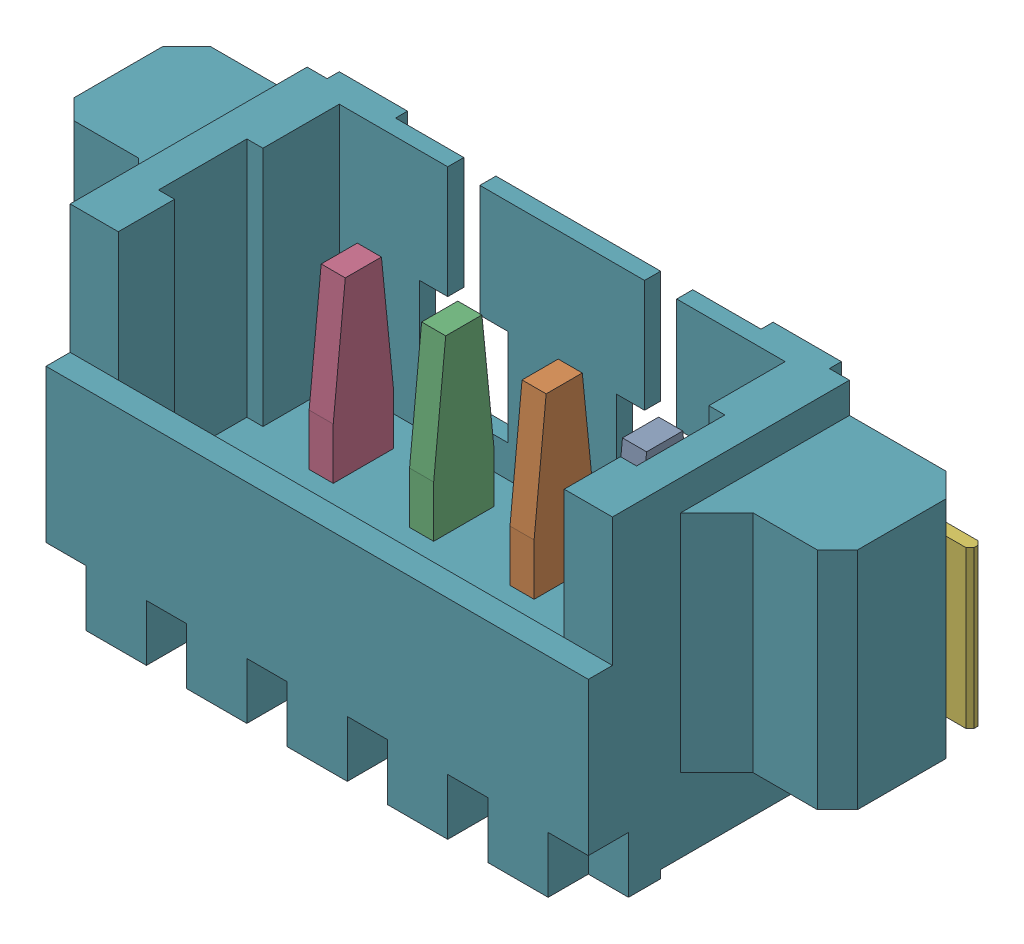
SolidWorks assembly J13, configuration Default. Lengths in mm.
Overall size (9.75 5.4 3.41).
8 component instances, 3 part files, 0 mates.
Components (placement in the parent):
- 653104131822-1: 653104131822 [Default] at (105.1001 84.1 1.69) x (-1 0 0) z (0 0 1) size (9.75 5.4 3.41)
  - 6531xx131822_PIN_2-1: 6531xx131822_PIN_2 [Default] at (-1.875 2.7 -0.425) x (1 0 0) z (0 -1 0) size (0.3 1.48 4.54)
  - 6531xx131822_PIN_2-2: 6531xx131822_PIN_2 [Default] at (-0.625 2.7 -0.425) x (1 0 0) z (0 -1 0) size (0.3 1.48 4.54)
  - 6531xx131822_PIN_2-3: 6531xx131822_PIN_2 [Default] at (0.625 2.7 -0.425) x (1 0 0) z (0 -1 0) size (0.3 1.48 4.54)
  - 6531xx131822_PIN_2-4: 6531xx131822_PIN_2 [Default] at (1.875 2.7 -0.425) x (1 0 0) z (0 -1 0) size (0.3 1.48 4.54)
  - 6531xx131822_PIN_FLANGE_2-1: 6531xx131822_PIN_FLANGE_2 [Default] at (3.75 -0.045 -1.05) size (1.25 1.95 1.4)
  - 6531xx131822_PIN_FLANGE_2-2: 6531xx131822_PIN_FLANGE_2 [Default] at (-3.75 -0.045 -1.05) x (-1 0 0) z (0 0 1) size (1.25 1.95 1.4)
  - 653104131822-1: 653104131822 [Default] at origin size (9.75 4.2 3.4)
